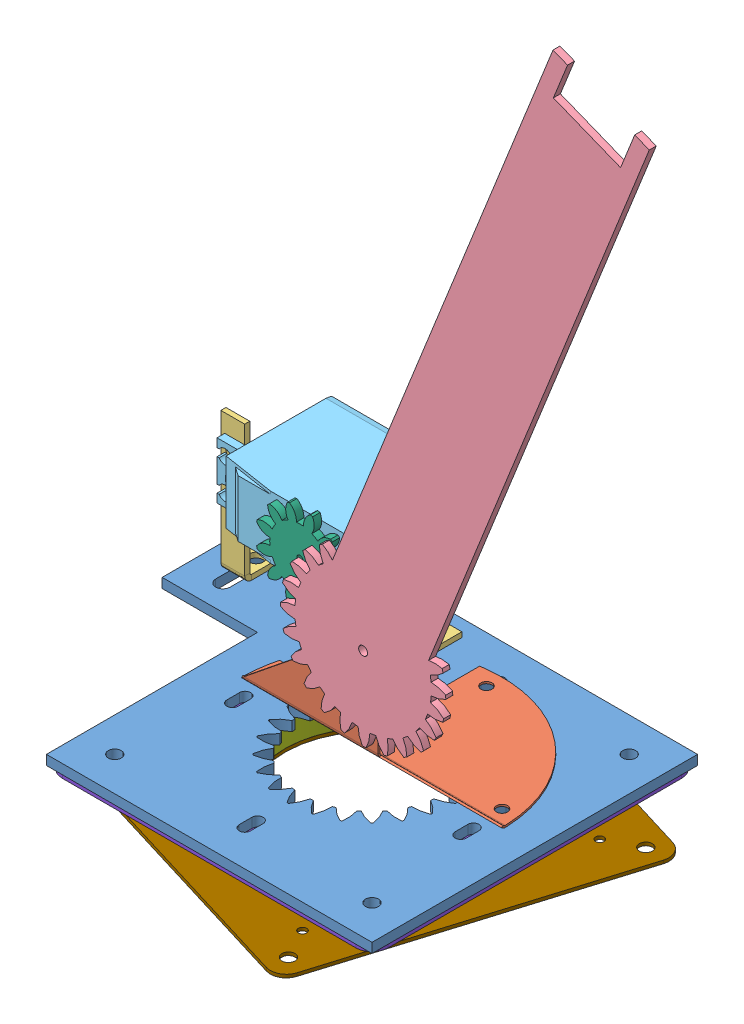
SolidWorks assembly crane arm, configuration Default. Lengths in mm.
Overall size (180.08 239.82 127.82).
12 component instances, 10 part files, 21 mates.
Components (placement in the parent):
- internal spur gear platform lazy susan-1: internal spur gear platform lazy susan [Default] at (61.2355 64.1042 98.7839) size (132.4 40.03 102.4)
- crane arm left pivot support-1: crane arm left pivot support [Default] at (61.2355 67.7542 98.7839) x (-1 0 0) z (0 -1 0) size (81.81 41.46 33.42)
- verical servo support-1: verical servo support [Default] at (-5.1145 68.7542 70.8723) x (0 0 1) z (-1 0 0) size (21.6 43.6 7.5)
- crane arm with gear and notch-1: crane arm with gear and notch [Default] at (101.2254 196.9018 99.3839) x (0.928633 -0.370999 0) z (-0.370999 -0.928633 0) size (51.69 2.2 227.68)
- Servo Motor-1: Servo Motor [Default] at (16.2434 96.2135 81.9465) x (0 1 0) z (0 0 -1) size (19.69 55.27 37.39)
- vertical gear mod 2 n 12 id 1.91-1: vertical gear mod 2 n 12 id 1.91 [Default] at (4.2532 106.3778 83.5721) size (27.23 27.23 2.35)
- verical servo support-2: verical servo support [Default] at (43.5855 68.7542 72.8723) x (0 0 1) z (-1 0 0) size (21.6 43.6 7.5)
- lazy susan 102.4 diameter-1: lazy susan 102.4 diameter [Default] at (47.0327 19.2593 29.5367) x (0.956476 0 0.29181) z (-0.29181 0 0.956476) size (127.82 77.77 127.82)
  - lazy susan bearing mockup-1: lazy susan bearing mockup [Default] at (33.7917 35.6948 62.0888) size (81.07 8.15 81.07)
  - lazy susan top 12.27 and 17.48-1: lazy susan top 12.27 and 17.48 [Default] at (33.7917 44.8448 62.0888) x (-0.956476 0 0.29181) z (-0.29181 0 -0.956476) size (102.4 68.62 102.4)
  - lazy susan bottom 8.2 and 14.83-1: lazy susan bottom 8.2 and 14.83 [Default] at (33.7917 35.6948 62.0888) size (102.4 38.91 102.4)
- crane arm right pivot support-1: crane arm right pivot support [Default] at (60.879 67.7542 102.7856) x (0.999951 0 -0.009904) z (0 -1 0) (suppressed, hidden)
Mates (geometry in assembly coordinates):
- Coincident1: coincident: plane of internal spur gear platform lazy susan-1 through (61.2355 67.1542 98.7839) normal (0 1 0); plane of crane arm left pivot support-1 through (61.2355 67.1542 98.8259) normal (0 -1 0)
- Concentric4: concentric aligned: circle of internal spur gear platform lazy susan-1; circle of crane arm left pivot support-1
- Parallel2: parallel aligned: line of internal spur gear platform lazy susan-1 through (10.0355 67.1542 149.9839) axis (1 0 0); line of crane arm left pivot support-1 through (63.7355 67.6412 98.9334) axis (1 0 0)
- Coincident14: coincident anti-aligned: plane of internal spur gear platform lazy susan-1 through (61.2355 67.1542 98.7839) normal (0 1 0); plane of verical servo support-1 through (-12.6145 67.1542 50.8723) normal (0 -1 0)
- Concentric5: concentric aligned: circle of internal spur gear platform lazy susan-1; circle of verical servo support-1
- Parallel3: parallel anti-aligned: line of internal spur gear platform lazy susan-1 through (112.4355 67.1542 47.5839) axis (-1 0 0); line of verical servo support-1 through (-12.6145 68.7542 50.8723) axis (1 0 0)
- Coincident17: coincident anti-aligned: plane of crane arm left pivot support-1 through (61.2355 67.7542 99.3839) normal (0 0 1); plane of crane arm with gear and notch-1 through (101.2254 196.9018 99.3839) normal (0 0 -1)
- Concentric6: concentric aligned: circle of crane arm left pivot support-1; circle of crane arm with gear and notch-1
- Concentric7: concentric anti-aligned: circle of verical servo support-1; circle of Servo Motor-1
- Coincident19: coincident anti-aligned: plane of verical servo support-1 through (-12.6145 68.7542 72.4723) normal (0 0 1); plane of Servo Motor-1 through (-11.3918 87.3235 72.4723) normal (0 0 -1)
- Parallel4: parallel anti-aligned: line of verical servo support-1 through (-12.6145 69.3542 72.4723) axis (0 1 0); line of Servo Motor-1 through (-11.3918 99.96 74.8853) axis (0 -1 0)
- Concentric9: concentric aligned: circle of Servo Motor-1; circle of vertical gear mod 2 n 12 id 1.91-1
- Coincident21: coincident anti-aligned: plane of Servo Motor-1 through (25.7049 96.2135 83.5721) normal (0 0 1); plane of vertical gear mod 2 n 12 id 1.91-1 through (30.6646 98.895 83.5721) normal (0 0 -1)
- Coincident22: coincident anti-aligned: plane of internal spur gear platform lazy susan-1 through (61.2355 67.1542 98.7839) normal (0 1 0); plane of verical servo support-2 through (36.0855 67.1542 52.8723) normal (0 -1 0)
- Concentric10: concentric aligned: circle of internal spur gear platform lazy susan-1; circle of verical servo support-2
- Parallel5: parallel anti-aligned: line of internal spur gear platform lazy susan-1 through (112.4355 67.1542 47.5839) axis (-1 0 0); line of verical servo support-2 through (36.0855 68.7542 52.8723) axis (1 0 0)
- Coincident24: coincident anti-aligned: plane of internal spur gear platform lazy susan-1 through (61.2355 64.1042 98.7839) normal (0 -1 0); plane of lazy susan 102.4 diameter-1/lazy susan top 12.27 and 17.48-1 through (107.4355 64.1042 52.5839) normal (0 1 0)
- Concentric11: concentric anti-aligned: circle of internal spur gear platform lazy susan-1; circle of lazy susan 102.4 diameter-1/lazy susan top 12.27 and 17.48-1
- Concentric12: concentric aligned: circle of internal spur gear platform lazy susan-1; circle of lazy susan 102.4 diameter-1/lazy susan top 12.27 and 17.48-1
- Coincident25: coincident anti-aligned: plane of internal spur gear platform lazy susan-1 through (61.2355 67.1542 98.7839) normal (0 1 0); plane of crane arm right pivot support-1 through (60.8786 67.1542 102.7436) normal (0 -1 0)
- Concentric13: concentric aligned: circle of internal spur gear platform lazy susan-1; circle of crane arm right pivot support-1
